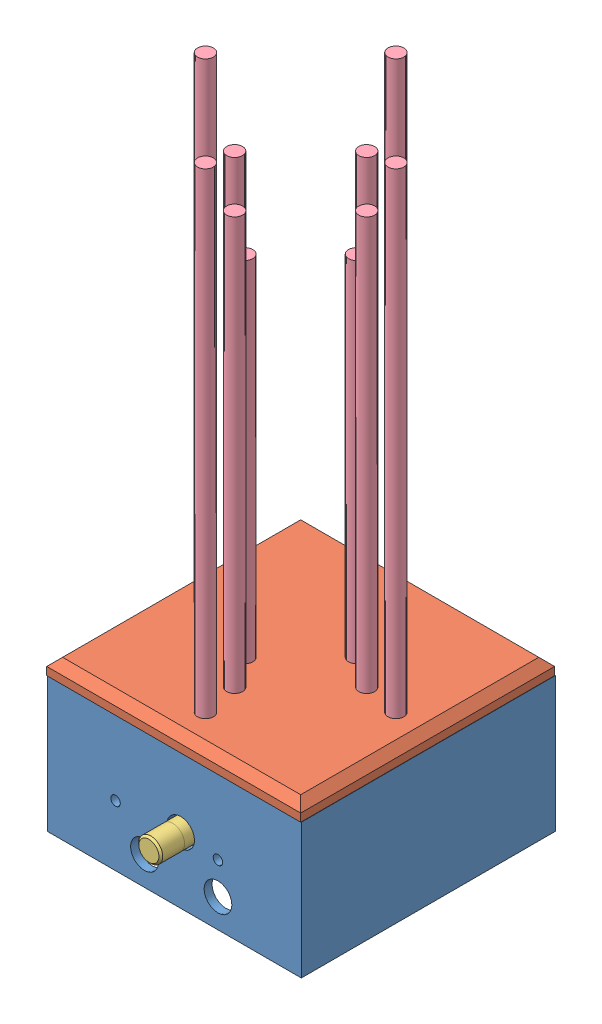
SolidWorks assembly Zeyn's Assembly, configuration Default. Lengths in mm.
Overall size (101.73 250.82 114.3).
13 component instances, 4 part files, 26 mates.
Components (placement in the parent):
- SchweykZeyn Base-1: SchweykZeyn Base [Default] at (110.3684 35.7301 -9.8062) x (-1 0 0) z (0 0 -1) size (101.6 53.98 101.6)
- SchweykZeyn Top Plate Rational Pattern-1: SchweykZeyn Top Plate Rational Pattern [Zeyn's Hole Pattern] at (110.2414 86.5301 -9.6792) size (101.6 9.53 101.6)
- SchweykZeyn Light Sculpture Knob-1: SchweykZeyn Light Sculpture Knob [Default] at (112.883 62.0191 44.1688) x (-0.923728 -0.383049 0) z (0 0 -1) size (9.53 9.53 28.58)
- SchweykZeyn Light Sculpture Rods-1: SchweykZeyn Light Sculpture Rods [7.875 inch] at (72.1414 86.5301 -9.6792) size (6.35 200.03 6.35)
- SchweykZeyn Light Sculpture Rods-2: SchweykZeyn Light Sculpture Rods [6.875 inches] at (86.7216 86.5301 -6.779) size (6.35 174.62 6.35)
- SchweykZeyn Light Sculpture Rods-11: SchweykZeyn Light Sculpture Rods [5.875 inches] at (99.0822 86.5301 1.48) x (0.982082 0 -0.188455) z (0.188455 0 0.982082) size (6.35 149.22 6.35)
- SchweykZeyn Light Sculpture Rods-12: SchweykZeyn Light Sculpture Rods [6.875 inches] at (107.3412 86.5301 13.8406) x (0.918365 0 -0.395734) z (0.395734 0 0.918365) size (6.35 174.62 6.35)
- SchweykZeyn Light Sculpture Rods-13: SchweykZeyn Light Sculpture Rods [7.875 inch] at (110.2414 86.5301 28.4208) x (0.8 0 -0.6) z (0.6 0 0.8) size (6.35 200.03 6.35)
- SchweykZeyn Light Sculpture Rods-14: SchweykZeyn Light Sculpture Rods [7.875 inch] at (148.3414 86.5301 -9.6792) x (0.63358 0 -0.773678) z (0.773678 0 0.63358) size (6.35 200.03 6.35)
- SchweykZeyn Light Sculpture Rods-15: SchweykZeyn Light Sculpture Rods [6.875 inches] at (133.7612 86.5301 -12.5794) x (0.443629 0 -0.896211) z (0.896211 0 0.443629) size (6.35 174.62 6.35)
- SchweykZeyn Light Sculpture Rods-16: SchweykZeyn Light Sculpture Rods [5.875 inches] at (121.4006 86.5301 -20.8384) x (0.263225 0 -0.964735) z (0.964735 0 0.263225) size (6.35 149.22 6.35)
- SchweykZeyn Light Sculpture Rods-17: SchweykZeyn Light Sculpture Rods [6.875 inches] at (113.1416 86.5301 -33.199) x (0.120178 0 -0.992752) z (0.992752 0 0.120178) size (6.35 174.62 6.35)
- SchweykZeyn Light Sculpture Rods-18: SchweykZeyn Light Sculpture Rods [7.875 inch] at (110.2414 86.5301 -47.7792) x (0.030377 0 -0.999538) z (0.999538 0 0.030377) size (6.35 200.03 6.35)
Mates (geometry in assembly coordinates):
- Coincident13: coincident anti-aligned: plane of SchweykZeyn Base-1 through (110.3684 89.7051 -9.8062) normal (0 1 0); plane of SchweykZeyn Top Plate Rational Pattern-1 through (110.2414 89.7051 -9.6792) normal (0 -1 0)
- Coincident14: coincident anti-aligned: plane of SchweykZeyn Base-1 through (157.9934 89.7051 37.8188) normal (0 0 -1); plane of SchweykZeyn Top Plate Rational Pattern-1 through (157.7394 89.7051 37.8188) normal (0 0 1)
- Coincident15: coincident anti-aligned: plane of SchweykZeyn Base-1 through (62.7434 89.7051 -57.4312) normal (1 0 0); plane of SchweykZeyn Top Plate Rational Pattern-1 through (62.7434 89.7051 37.8188) normal (-1 0 0)
- Concentric3: concentric aligned: cylinder of SchweykZeyn Base-1 through (112.883 62.0191 -60.6072) axis (0 0 1) radius 5.5626; cylinder of SchweykZeyn Light Sculpture Knob-1 through (112.883 62.0191 25.1188) axis (0 0 1) radius 4.7625
- Concentric4: concentric aligned: cylinder of SchweykZeyn Base-1 through (112.883 62.0191 -60.6072) axis (0 0 1) radius 5.5626; cylinder of SchweykZeyn Light Sculpture Knob-1 through (112.883 62.0191 25.1188) axis (0 0 1) radius 4.7625
- Distance1: distance = 12.7 mm aligned: plane of SchweykZeyn Base-1 through (161.1684 89.7051 40.9938) normal (0 0 1); plane of SchweykZeyn Light Sculpture Knob-1 through (112.883 62.0191 53.6938) normal (0 0 1)
- Concentric5: concentric anti-aligned: cylinder of SchweykZeyn Top Plate Rational Pattern-1 through (72.1414 86.5301 -9.6792) axis (0 1 0) radius 3.175; cylinder of SchweykZeyn Light Sculpture Rods-1 through (72.1414 286.5551 -9.6792) axis (0 -1 0) radius 3.175
- Coincident18: coincident aligned: plane of SchweykZeyn Top Plate Rational Pattern-1 through (110.2414 86.5301 -9.6792) normal (0 -1 0); plane of SchweykZeyn Light Sculpture Rods-1 through (72.1414 86.5301 -9.6792) normal (0 -1 0)
- Concentric6: concentric anti-aligned: cylinder of SchweykZeyn Top Plate Rational Pattern-1 through (86.7216 86.5301 -6.779) axis (0 1 0) radius 3.175; cylinder of SchweykZeyn Light Sculpture Rods-2 through (86.7216 261.1551 -6.779) axis (0 -1 0) radius 3.175
- Coincident19: coincident aligned: plane of SchweykZeyn Top Plate Rational Pattern-1 through (110.2414 86.5301 -9.6792) normal (0 -1 0); plane of SchweykZeyn Light Sculpture Rods-2 through (86.7216 86.5301 -6.779) normal (0 -1 0)
- Coincident20: coincident aligned: plane of SchweykZeyn Top Plate Rational Pattern-1 through (110.2414 86.5301 -9.6792) normal (0 -1 0); plane of SchweykZeyn Light Sculpture Rods-11 through (99.0822 86.5301 1.48) normal (0 -1 0)
- Concentric7: concentric anti-aligned: cylinder of SchweykZeyn Top Plate Rational Pattern-1 through (99.0822 86.5301 1.48) axis (0 1 0) radius 3.175; cylinder of SchweykZeyn Light Sculpture Rods-11 through (99.0822 235.7551 1.48) axis (0 -1 0) radius 3.175
- Coincident21: coincident aligned: plane of SchweykZeyn Top Plate Rational Pattern-1 through (110.2414 86.5301 -9.6792) normal (0 -1 0); plane of SchweykZeyn Light Sculpture Rods-12 through (107.3412 86.5301 13.8406) normal (0 -1 0)
- Concentric8: concentric anti-aligned: cylinder of SchweykZeyn Top Plate Rational Pattern-1 through (107.3412 86.5301 13.8406) axis (0 1 0) radius 3.175; cylinder of SchweykZeyn Light Sculpture Rods-12 through (107.3412 261.1551 13.8406) axis (0 -1 0) radius 3.175
- Coincident22: coincident aligned: plane of SchweykZeyn Top Plate Rational Pattern-1 through (110.2414 86.5301 -9.6792) normal (0 -1 0); plane of SchweykZeyn Light Sculpture Rods-13 through (110.2414 86.5301 28.4208) normal (0 -1 0)
- Concentric9: concentric anti-aligned: cylinder of SchweykZeyn Top Plate Rational Pattern-1 through (110.2414 86.5301 28.4208) axis (0 1 0) radius 3.175; cylinder of SchweykZeyn Light Sculpture Rods-13 through (110.2414 286.5551 28.4208) axis (0 -1 0) radius 3.175
- Coincident23: coincident aligned: plane of SchweykZeyn Top Plate Rational Pattern-1 through (110.2414 86.5301 -9.6792) normal (0 -1 0); plane of SchweykZeyn Light Sculpture Rods-14 through (148.3414 86.5301 -9.6792) normal (0 -1 0)
- Concentric10: concentric anti-aligned: cylinder of SchweykZeyn Top Plate Rational Pattern-1 through (148.3414 86.5301 -9.6792) axis (0 1 0) radius 3.175; cylinder of SchweykZeyn Light Sculpture Rods-14 through (148.3414 286.5551 -9.6792) axis (0 -1 0) radius 3.175
- Coincident24: coincident aligned: plane of SchweykZeyn Top Plate Rational Pattern-1 through (110.2414 86.5301 -9.6792) normal (0 -1 0); plane of SchweykZeyn Light Sculpture Rods-15 through (133.7612 86.5301 -12.5794) normal (0 -1 0)
- Concentric11: concentric anti-aligned: cylinder of SchweykZeyn Top Plate Rational Pattern-1 through (133.7612 86.5301 -12.5794) axis (0 1 0) radius 3.175; cylinder of SchweykZeyn Light Sculpture Rods-15 through (133.7612 261.1551 -12.5794) axis (0 -1 0) radius 3.175
- Coincident25: coincident aligned: plane of SchweykZeyn Top Plate Rational Pattern-1 through (110.2414 86.5301 -9.6792) normal (0 -1 0); plane of SchweykZeyn Light Sculpture Rods-16 through (121.4006 86.5301 -20.8384) normal (0 -1 0)
- Concentric12: concentric anti-aligned: cylinder of SchweykZeyn Top Plate Rational Pattern-1 through (121.4006 86.5301 -20.8384) axis (0 1 0) radius 3.175; cylinder of SchweykZeyn Light Sculpture Rods-16 through (121.4006 235.7551 -20.8384) axis (0 -1 0) radius 3.175
- Coincident26: coincident aligned: plane of SchweykZeyn Top Plate Rational Pattern-1 through (110.2414 86.5301 -9.6792) normal (0 -1 0); plane of SchweykZeyn Light Sculpture Rods-17 through (113.1416 86.5301 -33.199) normal (0 -1 0)
- Concentric13: concentric anti-aligned: cylinder of SchweykZeyn Top Plate Rational Pattern-1 through (113.1416 86.5301 -33.199) axis (0 1 0) radius 3.175; cylinder of SchweykZeyn Light Sculpture Rods-17 through (113.1416 261.1551 -33.199) axis (0 -1 0) radius 3.175
- Coincident27: coincident aligned: plane of SchweykZeyn Top Plate Rational Pattern-1 through (110.2414 86.5301 -9.6792) normal (0 -1 0); plane of SchweykZeyn Light Sculpture Rods-18 through (110.2414 86.5301 -47.7792) normal (0 -1 0)
- Concentric14: concentric anti-aligned: cylinder of SchweykZeyn Top Plate Rational Pattern-1 through (110.2414 86.5301 -47.7792) axis (0 1 0) radius 3.175; cylinder of SchweykZeyn Light Sculpture Rods-18 through (110.2414 286.5551 -47.7792) axis (0 -1 0) radius 3.175
